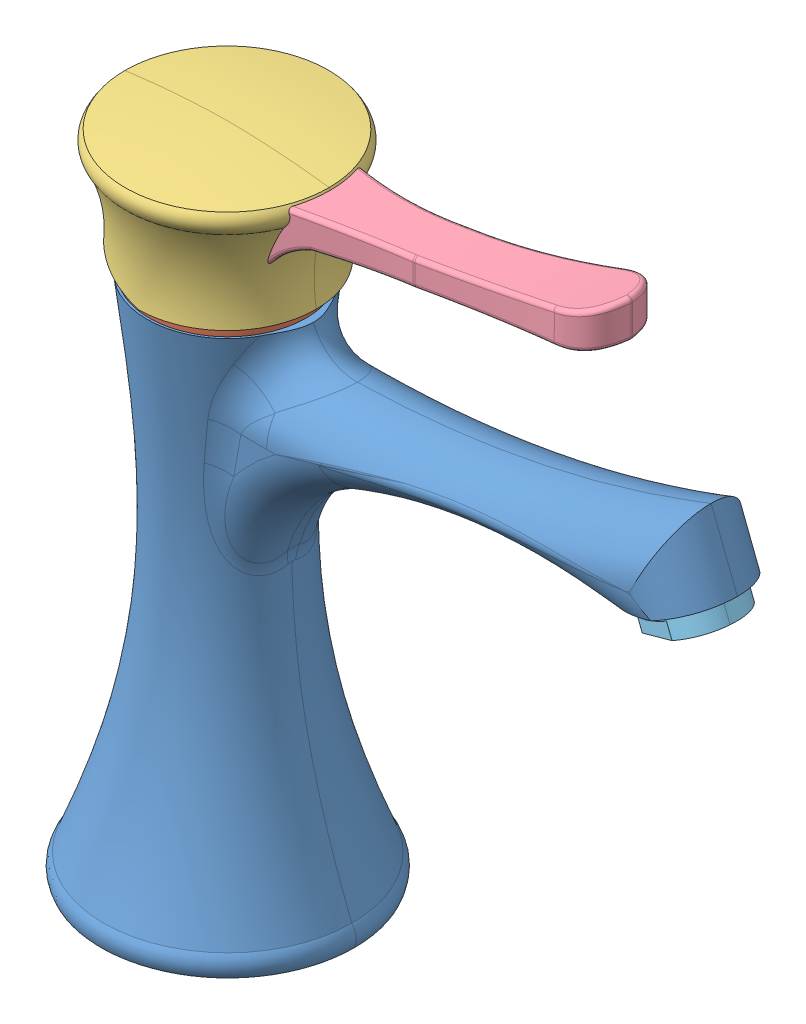
SolidWorks assembly 12032, configuration Default. Lengths in mm.
Overall size (162.94 169.45 122.41).
6 component instances, 5 part files, 0 mates.
Components (placement in the parent):
- lavabo belinda.IGS-1: lavabo belinda.IGS [Default] at origin size (162.94 169.45 122.41)
  - 0101203200.IGS.IGS.IGS-1: 0101203200.IGS.IGS.IGS [Default] at (-46.1098 -75.0658 154.3867) size (154.97 149.01 122.41)
  - cappuccio lavabo belinda.IGS.IGS.IGS-1: cappuccio lavabo belinda.IGS.IGS.IGS [Default] at (-46.1098 50.9342 154.3867) x (-0.991657 0 0.128903) z (-0.128903 0 -0.991657) size (44.73 11.01 75.81)
  - prova leva.IGS.IGS.IGS-1: prova leva.IGS.IGS.IGS [Default] at (-46.2966 53.9342 154.3899) x (0.999991 0 -0.00419) z (0.00419 0 0.999991) size (68.33 28.82 52.98)
  - prova MANIGLIA LEVA.IGS.IGS.IGS-1: prova MANIGLIA LEVA.IGS.IGS.IGS [Default] at (-49.2474 53.4343 154.4479) x (0.999991 0 -0.00419) z (0.00419 0.002016 0.999989) size (79.91 29.25 20.35)
  - 0000092400 belinda.IGS.IGS.IGS-1: 0000092400 belinda.IGS.IGS.IGS [Default] at (67.5754 35.7977 154.3867) x (0.13495 0.052744 -0.989448) z (0.921562 0.360182 0.144891) size (29.89 13.01 20.11)
